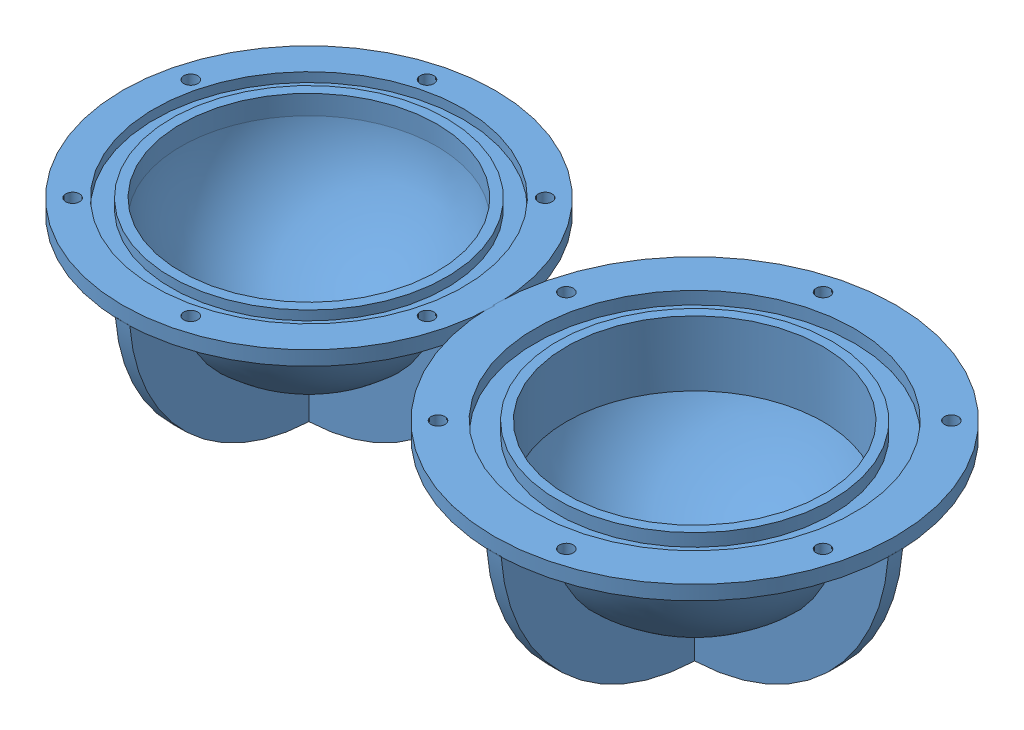
SolidWorks assembly Housing_Rev2_comparison, configuration Default. Lengths in mm.
Overall size (161.17 41.97 83.72).
2 component instances, 1 part files, 3 mates.
Components (placement in the parent):
- housing2_rev2-1: housing2_rev2 [2-140] at origin size (77.69 38.96 77.69)
- housing2_rev2-2: housing2_rev2 [2-228] at (80.4637 0 0) size (83.72 41.97 83.72)
Mates (geometry in assembly coordinates):
- Coincident1: coordinate: point of housing2_rev2-1
- Coincident2: coincident aligned: plane of housing2_rev2-2 through (80.4637 0 -7.2105) normal (0 1 0)
- Coincident5: coincident aligned: plane of housing2_rev2-2 through (80.4637 0 0) normal (0 0 1)
